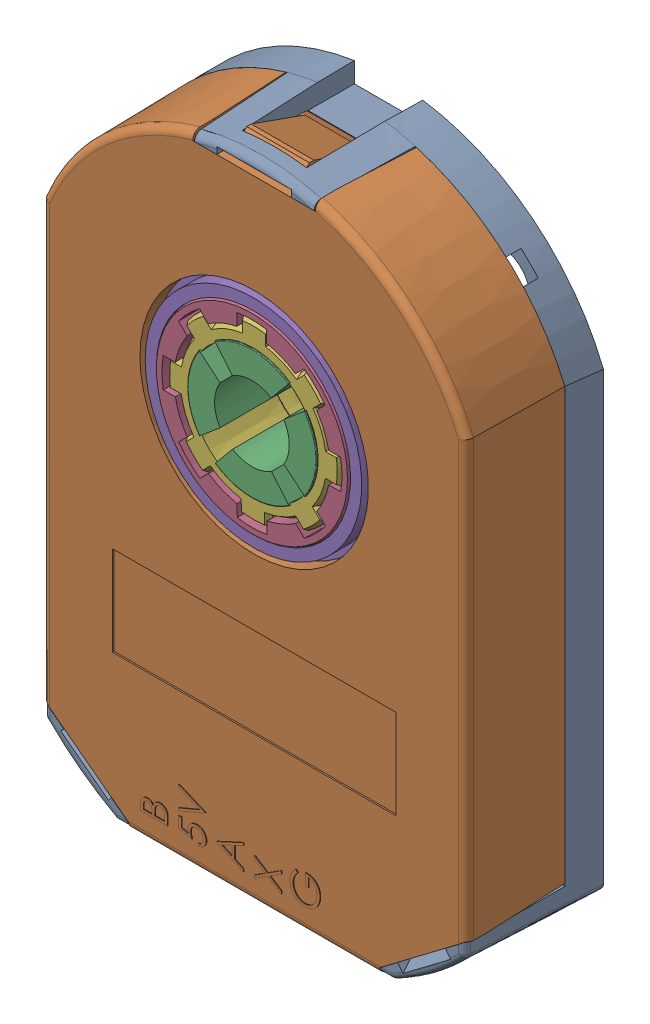
SolidWorks assembly Same_Sky_CUI_DEVICES_AMT102-0048-N5000-S, configuration Default. Lengths in mm.
Overall size (28.83 43.41 9.15).
9 component instances, 9 part files, 0 mates.
Components (placement in the parent):
- Same_Sky_AMT-102-Base-REV-K-1: Same_Sky_AMT-102-Base-REV-K [Default] x (-1 0 0) z (0 0 -1) size (28.83 43.41 9.03)
- Same_Sky_AMT-102-Top-Cover-REV-I-1: Same_Sky_AMT-102-Top-Cover-REV-I [Default] at (0 0 5.23) x (-1 0 0) z (0 0 -1) size (28.6 43.26 6.55) (hidden)
- Same_Sky_AMT-Sleeve-REV-D(5 mm)-1: Same_Sky_AMT-Sleeve-REV-D(5 mm) [Default] at (0 0 -2.42) x (0.999996 0.002864 0) z (0 0 1) size (10.79 10.79 7.8)
- Same_Sky_AMT-Hub-Top-REV-D1-1: Same_Sky_AMT-Hub-Top-REV-D1 [Default] at (0 0 2.13) x (0.999996 0.002864 0) z (0 0 1) size (14 14 5.67) (hidden)
- Same_Sky_AMT-Hub-Bottom-REV-B-1: Same_Sky_AMT-Hub-Bottom-REV-B [Default] at (0 0 2.43) x (0.999998 -0.001942 0) z (0 0 1) size (17.3 17.3 3.2) (hidden)
- Same_Sky_AMT10X-Shaft-Adaptor-REV-E-1: Same_Sky_AMT10X-Shaft-Adaptor-REV-E [Default] at (0 0 0.03) x (0.999996 0.002864 0) z (0 0 1) size (11.8 11.8 7.8)
- Same_Sky_Receiver-board-1: Same_Sky_Receiver-board [Default] at (72.2834 -20.351 3.03) x (-1 0 0) z (0 0 -1) size (26.5 26.62 0.41) (hidden)
- Same_Sky_Rotor-board-REV F-1: Same_Sky_Rotor-board-REV F [Default] at (0 0 2.13) x (0.807874 -0.589355 0) z (0 0 1) size (26 26 0.3) (hidden)
- Same_Sky_Transmitter-board AMT10(AMT-102)-1: Same_Sky_Transmitter-board AMT10(AMT-102) [Default] at (19.1596 -17.1102 1.22) x (-1 0 0) z (0 0 -1) size (26.63 38.43 4.41) (hidden)
